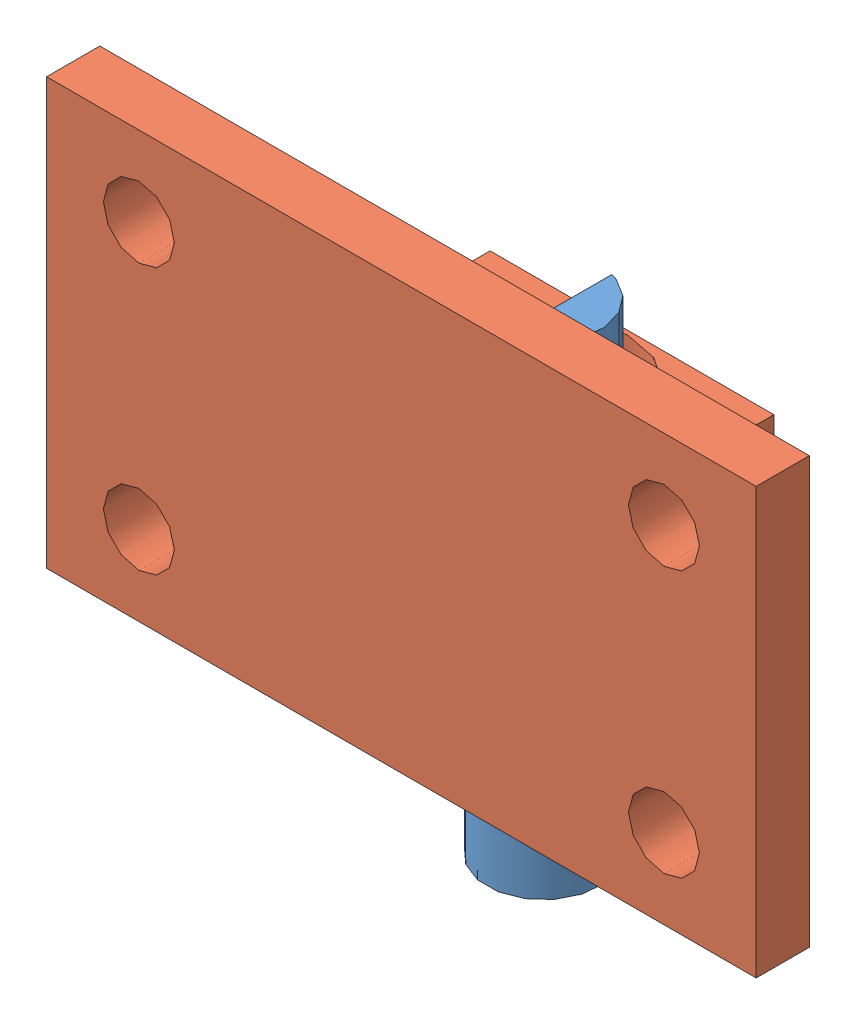
SolidWorks assembly 装配体2, configuration Default. Lengths in mm.
Overall size (40 31.94 13).
2 component instances, 2 part files, 1 mates.
Components (placement in the parent):
- vane_link_b-1: vane_link_b [Default] at (4.166 -28.0097 23.0403) size (6.35 27.15 6.35)
- vane_base_b-1: vane_base_b [Default] at (4.166 21.9335 31.0403) x (1 0 0) z (0 1 0) size (40 13 24)
Mates (geometry in assembly coordinates):
- 同心1: concentric anti-aligned: cylinder of vane_link_b-1 through (4.166 29.1403 23.0403) axis (0 -1 0) radius 3.175; cylinder of vane_base_b-1 through (4.166 14.9335 23.0403) axis (0 1 0) radius 4.7625
